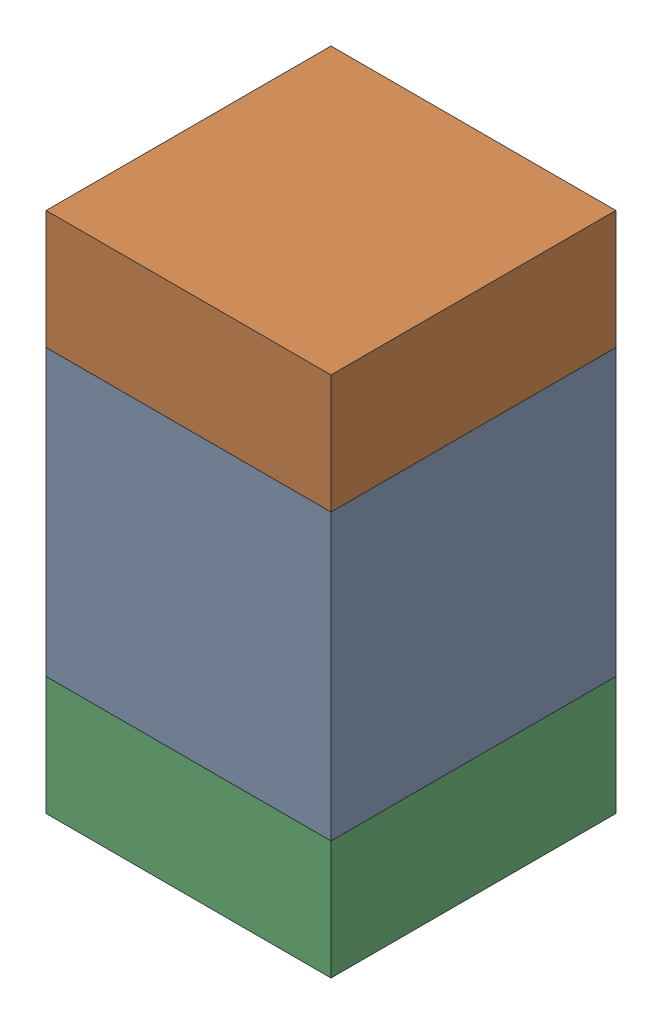
SolidWorks assembly C122_2PCB, configuration Default. Lengths in mm.
Overall size (0.6 1.1 0.6).
6 component instances, 2 part files, 0 mates.
Components (placement in the parent):
- 761606048-1: 761606048 [Default] at (106.5 100.1 0) size (0.6 0.6 0.6)
  - Extruded_9-1: Extruded_9 [Default] at origin size (0.6 0.6 0.6)
- 854785296-1: 854785296 [Default] at (106.5 100.525 0) size (0.6 0.25 0.6)
  - Extruded_10-1: Extruded_10 [Default] at origin size (0.6 0.25 0.6)
- 854785296-2: 854785296 [Default] at (106.5 99.675 0) size (0.6 0.25 0.6)
  - Extruded_10-1: Extruded_10 [Default] at origin size (0.6 0.25 0.6)
